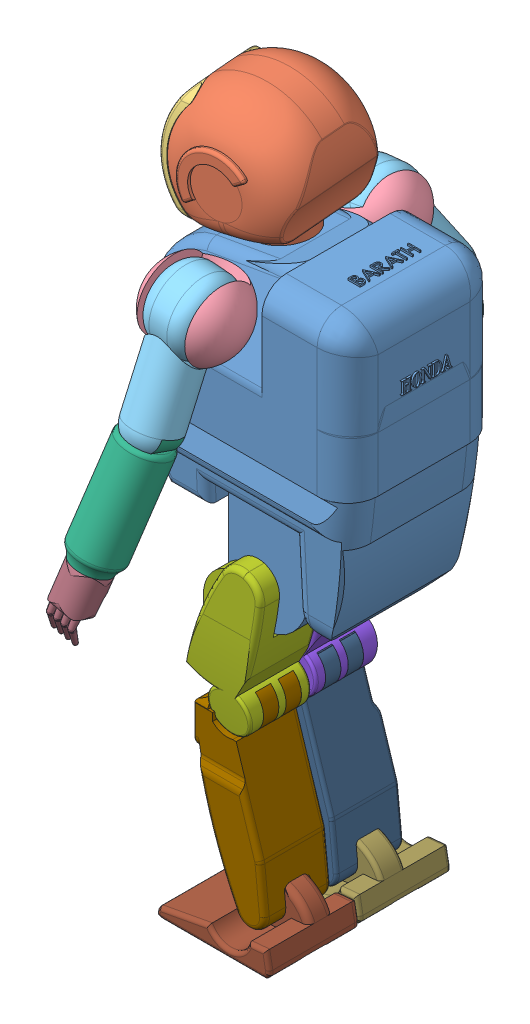
SolidWorks assembly Assem asimo, configuration Default. Lengths in mm.
Overall size (361.9 1145.7 741.54).
17 component instances, 14 part files, 31 mates.
Components (placement in the parent):
- body asimo-1: body asimo [Default] at (194.5895 297.6111 293.7925) size (353.05 528.29 256.4)
- head asimo-1: head asimo [Default] at (151.9487 627.5216 319.4292) x (0.99654 0 -0.083115) z (0.083115 0 0.99654) size (195 232.42 213.22)
- face mask asimo-1: face mask asimo [Default] at (151.8785 597.9322 320.6868) x (0.9965 -0.00899 -0.083111) z (0.083115 0 0.99654) size (54.7 166.34 186.45)
- arm  ball joint asimo-1: arm  ball joint asimo [Default] at (164.3259 433.6413 563.1918) x (0.998049 -0.057965 0.023183) z (0 0.371347 0.928494) size (140 114.89 147.45)
- arm  ball joint asimo-2: arm  ball joint asimo [Default] at (164.3259 433.6413 274.3932) x (0.98609 0.154329 0.061723) z (0 0.371347 -0.928494) size (140 114.89 147.45)
- arm limb asimo-1: arm limb asimo [Default] at (164.1744 436.3873 269.948) x (-0.028986 0.525327 -0.850407) z (-0.98609 -0.154329 -0.061723) size (101.47 242.09 80)
- arm limb asimo-2: arm limb asimo [Default] at (164.3118 435.3699 568.1249) x (-0.002715 0.330698 0.943733) z (0.998049 -0.057965 0.023183) size (101.47 242.09 80)
- hand wrist asimo-1: hand wrist asimo [Default] at (189.0546 304.8863 201.259) x (-0.413047 -0.781027 -0.46839) z (-0.028986 0.525327 -0.850407) size (254.64 80 80)
- hand wrist asimo-2: hand wrist asimo [Default] at (154.9872 290.3105 606.8614) x (-0.183046 -0.927955 0.324642) z (-0.002715 0.330698 0.943733) size (254.64 80 80)
- lefttigh asimo-1: lefttigh asimo [Default] at (159.5992 -124.6946 533.7336) x (0 0 1) z (-0.999864 -0.016495 0) size (111.34 254.01 129.5)
- right tigh asimo-1: right tigh asimo [Default] at (156.7473 -123.8511 302.8143) x (0 0 1) z (-1 0 0) size (113.84 254.01 132.66)
- left leg asimo-1: left leg asimo [Default] at (152.4204 -152.1737 423.7336) x (0 0 1) z (-1 0 0) size (110.72 316.18 123.1)
- right leg asimo-1: right leg asimo [Default] at (149.1306 -151.6139 412.8143) x (0 0 1) z (-1 0 0) size (110.46 316.68 123.1)
- left leg toes asimo-1: left leg toes asimo [Default] at (220.5203 -408.2799 418.7336) size (184.55 82.49 151.26)
- right leg toes asimo-1: right leg toes asimo [Default] at (217.2305 -407.7201 417.8143) size (184.54 82.49 150.97)
- left hand-1: left hand [Default] at (118.3236 111.3334 690.6645) x (0.982621 -0.183046 0.030823) z (-0.030823 -0.324642 -0.945334) size (60.64 102.09 72.35)
- right hand-1: right hand [Default] at (105.8654 159.1874 90.573) x (-0.907286 0.397455 0.137341) z (-0.078897 -0.481691 0.872782) size (60.64 102.09 72.35)
Mates (geometry in assembly coordinates):
- Concentric1: concentric: cylinder of assembly; cylinder of assembly; cylinder of body asimo-1 through (163.7448 457.5216 418.7925) axis (0 1 0) radius 45; cylinder of head asimo-1 through (163.7448 632.3495 418.7925) axis (0 -1 0) radius 45
- Coincident1: coincident: plane of assembly; plane of assembly; plane of body asimo-1 through (163.7448 457.5216 418.7925) normal (0 1 0); plane of head asimo-1 through (163.7448 457.5216 418.7925) normal (0 -1 0)
- Concentric5: concentric: cylinder of assembly; cylinder of assembly; cylinder of head asimo-1 through (170.4822 584.597 518.5778) axis (-0.083115 0 -0.99654) radius 105.9696; cylinder of face mask asimo-1 through (170.5858 584.597 519.8209) axis (-0.083115 0 -0.99654) radius 105.9696
- Concentric8: concentric: cylinder of assembly; cylinder of assembly; cylinder of body asimo-1 through (164.3259 400.22 479.6274) axis (0 0.371347 0.928494) radius 10; cylinder of arm  ball joint asimo-1 through (164.3259 400.22 479.6274) axis (0 0.371347 0.928494) radius 10
- Concentric9: concentric: sphere of assembly; sphere of assembly; sphere of body asimo-1; sphere of arm  ball joint asimo-1
- Concentric10: concentric: cylinder of assembly; cylinder of assembly; cylinder of body asimo-1 through (164.3259 400.22 357.9577) axis (0 0.371347 -0.928494) radius 10; cylinder of arm  ball joint asimo-2 through (164.3259 400.22 357.9577) axis (0 0.371347 -0.928494) radius 10
- Concentric11: concentric: sphere of assembly; sphere of assembly; sphere of body asimo-1; sphere of arm  ball joint asimo-2
- Coincident10: coincident: cylinder of assembly; circle of assembly; cylinder of arm  ball joint asimo-2 through (231.6604 444.1795 278.6079) axis (-0.98609 -0.154329 -0.061723) radius 10; circle of arm limb asimo-1
- Coincident11: coincident: plane of assembly; plane of assembly; plane of arm  ball joint asimo-2 through (158.1251 270.3468 133.6933) normal (0.98609 0.154329 0.061723); plane of arm limb asimo-1 through (124.7308 430.2141 267.4791) normal (-0.98609 -0.154329 -0.061723)
- Concentric14: concentric: cylinder of assembly; cylinder of assembly; cylinder of arm  ball joint asimo-1 through (232.477 429.6832 564.7748) axis (-0.998049 0.057965 -0.023183) radius 10; cylinder of arm limb asimo-2 through (124.404 435.9599 562.2645) axis (0.998049 -0.057965 0.023183) radius 10
- Coincident12: coincident: plane of assembly; plane of assembly; plane of arm  ball joint asimo-1 through (136.8898 647.2908 553.1345) normal (0.998049 -0.057965 0.023183); plane of arm limb asimo-2 through (124.3898 437.6885 567.1976) normal (-0.998049 0.057965 -0.023183)
- Concentric15: concentric: cylinder of assembly; cylinder of assembly; cylinder of arm limb asimo-1 through (187.0752 340.7579 143.1896) axis (0.028986 -0.525327 0.850407) radius 10; cylinder of hand wrist asimo-1 through (187.8951 325.8994 167.2427) axis (0.028986 -0.525327 0.850407) radius 10
- Coincident13: coincident: plane of assembly; plane of assembly; plane of arm limb asimo-1 through (203.9481 436.5777 282.1018) normal (-0.028986 0.525327 -0.850407); plane of hand wrist asimo-1 through (189.0546 304.8863 201.259) normal (0.028986 -0.525327 0.850407)
- Concentric16: concentric: cylinder of assembly; cylinder of assembly; cylinder of arm limb asimo-2 through (154.8018 312.8919 671.3035) axis (0.002715 -0.330698 -0.943733) radius 10; cylinder of hand wrist asimo-2 through (154.8786 303.5384 644.6107) axis (0.002715 -0.330698 -0.943733) radius 10
- Coincident14: coincident: plane of assembly; plane of assembly; plane of arm limb asimo-2 through (124.4207 433.9223 556.4498) normal (-0.002715 0.330698 0.943733); plane of hand wrist asimo-2 through (154.9872 290.3105 606.8614) normal (0.002715 -0.330698 -0.943733)
- Concentric17: concentric: cylinder of assembly; cylinder of assembly; cylinder of body asimo-1 through (209.3104 48.4695 546.5922) axis (0 0 -1) radius 10; cylinder of lefttigh asimo-1 through (209.3104 48.4695 530.0178) axis (0 0 -1) radius 10
- Coincident15: coincident: plane of assembly; plane of assembly; plane of body asimo-1 through (154.5895 152.6111 501.7336) normal (0 0 1); plane of lefttigh asimo-1 through (240.837 -123.3544 501.7336) normal (0 0 -1)
- Concentric18: concentric: cylinder of assembly; cylinder of assembly; cylinder of body asimo-1 through (209.3104 48.4695 546.5922) axis (0 0 -1) radius 10; cylinder of right tigh asimo-1 through (209.3104 48.4695 409.1357) axis (0 0 -1) radius 10
- Coincident16: coincident: plane of assembly; plane of assembly; plane of body asimo-1 through (154.5895 152.6111 335.8515) normal (0 0 -1); plane of right tigh asimo-1 through (237.9962 68.4695 335.8515) normal (0 0 1)
- Concentric19: concentric: cylinder of assembly; cylinder of assembly; cylinder of lefttigh asimo-1 through (177.0227 -151.099 273.4493) axis (0 0 1) radius 10; cylinder of left leg asimo-1 through (177.0227 -151.099 423.7336) axis (0 0 1) radius 10
- Coincident17: coincident: plane of assembly; plane of assembly; plane of lefttigh asimo-1 through (240.837 -123.3544 439.7336) normal (0 0 1); plane of left leg asimo-1 through (152.4204 -152.1737 439.7336) normal (0 0 -1)
- Concentric20: concentric: cylinder of assembly; cylinder of assembly; cylinder of right tigh asimo-1 through (173.7329 -150.5393 425.0986) axis (0 0 -1) radius 10; cylinder of right leg asimo-1 through (173.7329 -150.5393 522.8143) axis (0 0 -1) radius 10
- Coincident18: coincident: plane of assembly; plane of assembly; plane of right tigh asimo-1 through (237.9962 -123.8511 396.8143) normal (0 0 -1); plane of right leg asimo-1 through (149.1306 -151.6139 396.8143) normal (0 0 1)
- Concentric21: concentric: cylinder of assembly; cylinder of assembly; cylinder of left leg asimo-1 through (220.5203 -408.2799 430.4493) axis (0 0 1) radius 10; cylinder of left leg toes asimo-1 through (220.5203 -408.2799 418.7336) axis (0 0 1) radius 10
- Coincident19: coincident: plane of assembly; plane of assembly; plane of left leg asimo-1 through (245.5203 -483.2799 458.7336) normal (0 0 1); plane of left leg toes asimo-1 through (220.5203 -408.2799 458.7336) normal (0 0 -1)
- Concentric22: concentric: cylinder of assembly; cylinder of assembly; cylinder of right leg asimo-1 through (217.2305 -407.7201 419.5301) axis (0 0 1) radius 10; cylinder of right leg toes asimo-1 through (217.2305 -407.7201 568.2997) axis (0 0 -1) radius 10
- Coincident20: coincident: plane of assembly; plane of assembly; plane of right leg asimo-1 through (217.2305 -407.7201 377.8143) normal (0 0 -1); plane of right leg toes asimo-1 through (217.2305 -407.7201 377.8143) normal (0 0 1)
- Concentric23: concentric: cylinder of assembly; cylinder of assembly; cylinder of hand wrist asimo-2 through (114.6626 92.7742 697.1574) axis (0.183046 0.927955 -0.324642) radius 10; cylinder of left hand-1 through (114.6626 92.7742 697.1574) axis (0.183046 0.927955 -0.324642) radius 10
- Coincident21: coincident: plane of assembly; plane of assembly; plane of hand wrist asimo-2 through (114.6626 92.7742 697.1574) normal (-0.183046 -0.927955 0.324642); plane of left hand-1 through (114.6626 92.7742 697.1574) normal (0.183046 0.927955 -0.324642)
- Concentric24: concentric: cylinder of assembly; cylinder of assembly; cylinder of hand wrist asimo-1 through (97.6045 143.5669 81.2052) axis (0.413047 0.781027 0.46839) radius 10; cylinder of right hand-1 through (97.6045 143.5669 81.2052) axis (0.413047 0.781027 0.46839) radius 10
- Coincident22: coincident: plane of assembly; plane of assembly; plane of hand wrist asimo-1 through (97.6045 143.5669 81.2052) normal (-0.413047 -0.781027 -0.46839); plane of right hand-1 through (97.6045 143.5669 81.2052) normal (0.413047 0.781027 0.46839)
